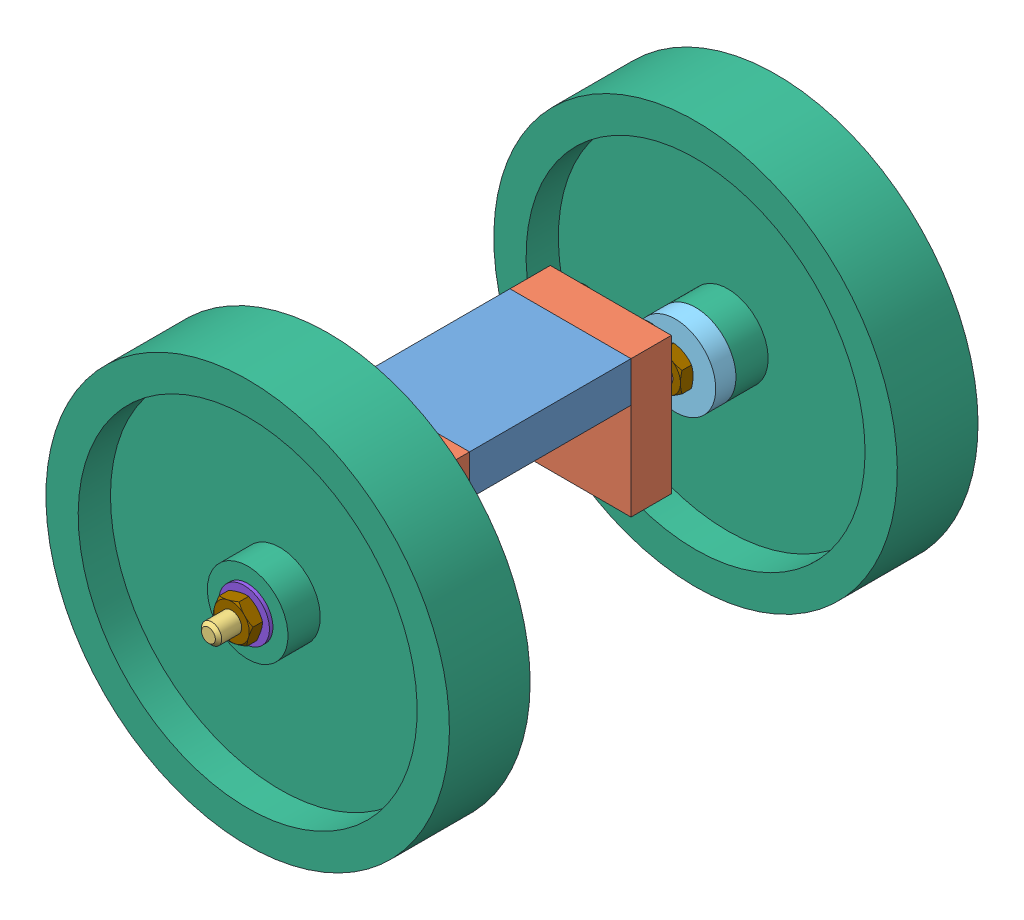
SolidWorks assembly rear axle assembly, configuration Default. Lengths in mm.
Overall size (137.94 137.94 191.03).
19 component instances, 9 part files, 39 mates.
Components (placement in the parent):
- Connection Rear Suspention-1: Connection Rear Suspention [Default] at (34.964 50.3299 109.0743) size (38.1 12.7 50.8)
- suspension rear-1: suspension rear [Default] at (15.914 13.4999 121.7743) size (38.1 43.18 12.7)
- suspension rear-3: suspension rear [Default] at (15.914 13.4999 58.2743) size (38.1 43.18 12.7)
- threaded axle rear left-1: threaded axle rear left [Default] at (34.964 28.7399 172.2163) x (0.913913 -0.405911 0) z (0 0 1) size (6.35 6.35 63.14)
- threaded axle rear right-1: threaded axle rear right [Default] at (34.964 28.7399 58.2743) x (0.899499 -0.436922 0) z (0 0 1) size (6.35 6.35 77.09)
- muffle rear wheels-1: muffle rear wheels [Default] at (34.964 28.7399 25.2543) x (-0.147836 -0.989012 0) z (0 0 -1) size (25.4 25.4 31.75)
- muffle rear wheels-2: muffle rear wheels [Default] at (34.964 28.7399 128.1243) x (0.995012 -0.099759 0) z (0 0 1) size (25.4 25.4 31.75)
- Wheel-1: Wheel [Default] at (34.964 28.7399 147.1743) x (-0.032877 -0.999459 0) z (0 0 1) size (127 127 25.4)
- Wheel-2: Wheel [Default] at (34.964 28.7399 6.2043) x (-0.090252 -0.995919 0) z (0 0 1) size (127 127 25.4)
- Button Head Hex Drive Screw 1-4-28-1: Button Head Hex Drive Screw 1-4-28 [Default] at (95.9461 40.1179 76.4889) size (11.1 11.1 16.71)
- Button Head Hex Drive Screw 1-4-28-2: Button Head Hex Drive Screw 1-4-28 [Default] at (75.6261 40.1179 76.4889) size (11.1 11.1 16.71)
- Button Head Hex Drive Screw 1-4-28-3: Button Head Hex Drive Screw 1-4-28 [Default] at (25.1415 2.4981 90.8598) x (-0.559698 -0.828696 0) z (0 0 -1) size (11.1 11.1 16.71)
- Button Head Hex Drive Screw 1-4-28-4: Button Head Hex Drive Screw 1-4-28 [Default] at (27.966 -1.4116 90.8598) x (-0.136827 -0.990595 0) z (0 0 -1) size (11.1 11.1 16.71)
- 316 Stainless Steel Washer-1: 316 Stainless Steel Washer [Default] at (69.8536 -6.45 -6.796) x (1 0 0) z (0 1 0) size (15.87 1.09 15.87)
- Stainless Steel Thin Hex Nut 1-4-28-1: Stainless Steel Thin Hex Nut 1-4-28 [Default] at (79.493 -4.5958 13.2545) x (0.988533 -0.151006 0) z (0.151006 0.988533 0) size (11.11 4.67 12.83)
- Stainless Steel Thin Hex Nut 1-4-28-2: Stainless Steel Thin Hex Nut 1-4-28 [Default] at (84.0162 2.5107 50.0655) x (1 0 0) z (0 1 0) size (11.11 4.67 12.83)
- Stainless Steel Thin Hex Nut 1-4-28-3: Stainless Steel Thin Hex Nut 1-4-28 [Default] at (89.5431 39.474 140.1242) x (0.956264 -0.292503 0) z (-0.292503 -0.956264 0) size (11.11 4.67 12.83)
- Stainless Steel Thin Hex Nut 1-4-28-4: Stainless Steel Thin Hex Nut 1-4-28 [Default] at (84.0162 54.9691 103.3132) x (1 0 0) z (0 -1 0) size (11.11 4.67 12.83)
- 316 Stainless Steel Washer-2: 316 Stainless Steel Washer [Default] at (69.8536 -6.45 160.6662) x (1 0 0) z (0 1 0) size (15.87 1.09 15.87)
Mates (geometry in assembly coordinates):
- Coincident1: coincident: plane of Connection Rear Suspention-1 through (34.964 50.3299 58.2743) normal (0 0 -1); plane of suspension rear-3 through (15.914 13.4999 58.2743) normal (0 0 1)
- Concentric1: concentric: circle of Connection Rear Suspention-1; circle of suspension rear-3
- Coincident2: coincident: plane of Connection Rear Suspention-1 through (34.964 50.3299 109.0743) normal (0 0 1); plane of suspension rear-1 through (15.914 13.4999 109.0743) normal (0 0 -1)
- Concentric2: concentric: circle of Connection Rear Suspention-1; cylinder of suspension rear-1 through (24.804 50.3299 121.7743) axis (0 0 1) radius 3.3735
- Coincident6: coincident: plane of Connection Rear Suspention-1 through (15.914 56.6799 58.2743) normal (0 1 0); plane of suspension rear-1 through (15.914 56.6799 109.0743) normal (0 1 0)
- Coincident29: coincident: plane of Connection Rear Suspention-1 through (15.914 56.6799 58.2743) normal (0 1 0); plane of suspension rear-3 through (15.914 56.6799 45.5743) normal (0 1 0)
- Coincident30: coincident: plane of Connection Rear Suspention-1 through (15.914 56.6799 58.2743) normal (0 1 0); plane of suspension rear-1 through (15.914 56.6799 109.0743) normal (0 1 0)
- Concentric9: concentric: cylinder of suspension rear-1 through (34.964 28.7399 121.7743) axis (0 0 1) radius 2.7051; circle of threaded axle rear left-1
- Coincident31: coincident: plane of suspension rear-1 through (15.914 13.4999 109.0743) normal (0 0 -1); plane of threaded axle rear left-1 through (34.964 28.7399 109.0743) normal (0 0 -1)
- Concentric10: concentric: cylinder of suspension rear-3 through (34.964 28.7399 58.2743) axis (0 0 1) radius 2.7051; circle of threaded axle rear right-1
- Coincident32: coincident: plane of suspension rear-3 through (15.914 13.4999 58.2743) normal (0 0 1); plane of threaded axle rear right-1 through (34.964 28.7399 58.2743) normal (0 0 1)
- Concentric19: concentric: cylinder of threaded axle rear right-1 through (34.964 28.7399 -18.8117) axis (0 0 1) radius 3.175; circle of muffle rear wheels-1
- Distance3: distance = 20.32 mm: plane of muffle rear wheels-1 through (34.964 28.7399 25.2543) normal (0 0 1); plane of suspension rear-3 through (15.914 13.4999 45.5743) normal (0 0 -1)
- Concentric21: concentric: cylinder of muffle rear wheels-1 through (34.964 28.7399 18.9043) axis (0 0 -1) radius 3.9751; circle of Wheel-2
- Coincident48: coincident: plane of muffle rear wheels-1 through (34.964 28.7399 18.9043) normal (0 0 -1); plane of Wheel-2 through (34.964 28.7399 18.9043) normal (0 0 1)
- Concentric23: concentric: cylinder of threaded axle rear left-1 through (34.964 28.7399 109.0743) axis (0 0 1) radius 3.175; circle of muffle rear wheels-2
- Distance4: distance = 6.35 mm: plane of muffle rear wheels-2 through (34.964 28.7399 128.1243) normal (0 0 -1); plane of suspension rear-1 through (15.914 13.4999 121.7743) normal (0 0 1)
- Concentric26: concentric: cylinder of muffle rear wheels-2 through (34.964 28.7399 134.4743) axis (0 0 1) radius 3.9751; cylinder of Wheel-1 through (34.964 28.7399 134.4743) axis (0 0 1) radius 3.9688
- Coincident54: coincident: plane of muffle rear wheels-2 through (34.964 28.7399 134.4743) normal (0 0 1); plane of Wheel-1 through (34.964 28.7399 134.4743) normal (0 0 -1)
- Concentric31: concentric: circle of threaded axle rear left-1; circle of Stainless Steel Thin Hex Nut 1-4-28-3
- Concentric32: concentric: circle of threaded axle rear left-1; circle of Stainless Steel Thin Hex Nut 1-4-28-4
- Coincident60: coincident: plane of muffle rear wheels-2 through (34.964 28.7399 128.1243) normal (0 0 -1); plane of Stainless Steel Thin Hex Nut 1-4-28-4 through (29.4077 31.9478 128.1243) normal (0 0 1)
- Concentric33: concentric: circle of threaded axle rear right-1; circle of Stainless Steel Thin Hex Nut 1-4-28-2
- Coincident61: coincident: plane of muffle rear wheels-1 through (34.964 28.7399 25.2543) normal (0 0 1); plane of Stainless Steel Thin Hex Nut 1-4-28-2 through (29.4077 25.532 25.2543) normal (0 0 -1)
- Concentric34: concentric: circle of threaded axle rear right-1; circle of Stainless Steel Thin Hex Nut 1-4-28-1
- Concentric35: concentric: circle of 316 Stainless Steel Washer-2; circle of threaded axle rear left-1
- Coincident63: coincident: circle of muffle rear wheels-2; plane of 316 Stainless Steel Washer-2 through (34.964 28.7399 159.8743) normal (0 0 -1)
- Coincident64: coincident: plane of Stainless Steel Thin Hex Nut 1-4-28-3 through (30.589 33.4327 160.9665) normal (0 0 -1); plane of 316 Stainless Steel Washer-2 through (34.964 28.7399 160.9665) normal (0 0 1)
- Coincident65: coincident: circle of muffle rear wheels-1; plane of 316 Stainless Steel Washer-1 through (34.964 28.7399 -6.4957) normal (0 0 1)
- Concentric36: concentric: circle of threaded axle rear right-1; circle of 316 Stainless Steel Washer-1
- Coincident66: coincident: plane of 316 Stainless Steel Washer-1 through (34.964 28.7399 -7.5879) normal (0 0 -1); plane of Stainless Steel Thin Hex Nut 1-4-28-1 through (28.987 26.4078 -7.5879) normal (0 0 1)
- Concentric37: concentric: circle of suspension rear-1; circle of Button Head Hex Drive Screw 1-4-28-1
- Coincident67: coincident: plane of suspension rear-1 through (15.914 13.4999 121.7743) normal (0 0 1); plane of Button Head Hex Drive Screw 1-4-28-1 through (45.124 55.8798 121.7743) normal (0 0 -1)
- Concentric38: concentric: circle of suspension rear-1; circle of Button Head Hex Drive Screw 1-4-28-2
- Coincident68: coincident: plane of suspension rear-1 through (15.914 13.4999 121.7743) normal (0 0 1); plane of Button Head Hex Drive Screw 1-4-28-2 through (24.804 55.8798 121.7743) normal (0 0 -1)
- Concentric39: concentric: circle of suspension rear-3; circle of Button Head Hex Drive Screw 1-4-28-4
- Coincident69: coincident: plane of suspension rear-3 through (15.914 13.4999 45.5743) normal (0 0 -1); plane of Button Head Hex Drive Screw 1-4-28-4 through (19.3063 51.0893 45.5743) normal (0 0 1)
- Concentric40: concentric: circle of suspension rear-3; circle of Button Head Hex Drive Screw 1-4-28-3
- Coincident70: coincident: plane of suspension rear-3 through (15.914 13.4999 45.5743) normal (0 0 -1); plane of Button Head Hex Drive Screw 1-4-28-3 through (40.5248 53.4362 45.5743) normal (0 0 1)
